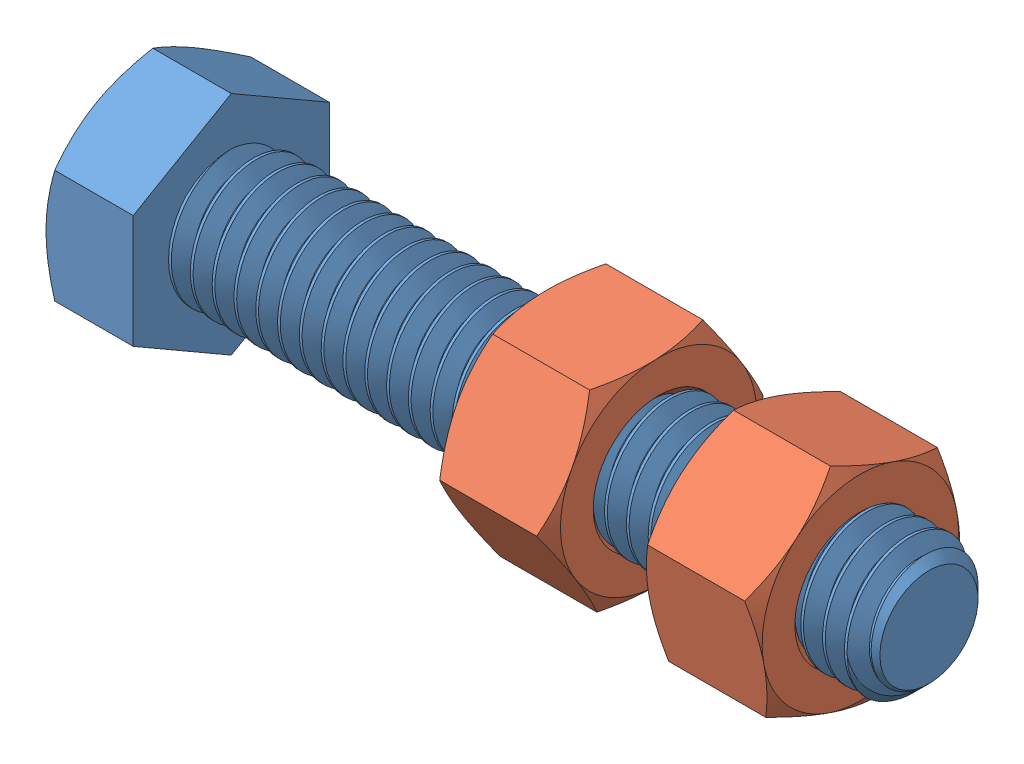
SolidWorks assembly ASSY_STAND, configuration Default. Lengths in mm.
Overall size (57.9 21.59 21.82).
3 component instances, 2 part files, 4 mates.
Components (placement in the parent):
- 91309A632_LOW-STRENGTH ZINC-PLATED STEEL CAP SCREW-1: 91309A632_LOW-STRENGTH ZINC-PLATED STEEL CAP SCREW [91309A632] at origin size (57.9 16.5 14.29)
- 90473A031_LOW-STRENGTH STEEL HEX NUT-1: 90473A031_LOW-STRENGTH STEEL HEX NUT [90473A031] at (4.7234 0 0) x (0 0.999304 0.037312) z (-1 0 0) size (14.29 16.5 10.6)
- 90473A031_LOW-STRENGTH STEEL HEX NUT-2: 90473A031_LOW-STRENGTH STEEL HEX NUT [90473A031] at (19.4078 0 0) x (0 -0.757844 -0.652435) z (1 0 0) size (14.29 16.5 10.6)
Mates (geometry in assembly coordinates):
- Concentric1: concentric: circle of 91309A632_LOW-STRENGTH ZINC-PLATED STEEL CAP SCREW-1; circle of 90473A031_LOW-STRENGTH STEEL HEX NUT-1
- Concentric2: concentric: circle of 91309A632_LOW-STRENGTH ZINC-PLATED STEEL CAP SCREW-1; circle of 90473A031_LOW-STRENGTH STEEL HEX NUT-2
- Distance1: distance = 5 mm aligned: plane of 90473A031_LOW-STRENGTH STEEL HEX NUT-2 through (23.575 8.1048 1.5351) normal (1 0 0); plane of 91309A632_LOW-STRENGTH ZINC-PLATED STEEL CAP SCREW-1 through (28.575 0 0) normal (1 0 0)
- Distance2: distance = 6.35 mm anti-aligned: plane of 90473A031_LOW-STRENGTH STEEL HEX NUT-1 through (8.8906 -6.9849 -4.3881) normal (1 0 0); plane of 90473A031_LOW-STRENGTH STEEL HEX NUT-2 through (15.2406 8.1048 1.5351) normal (-1 0 0)
